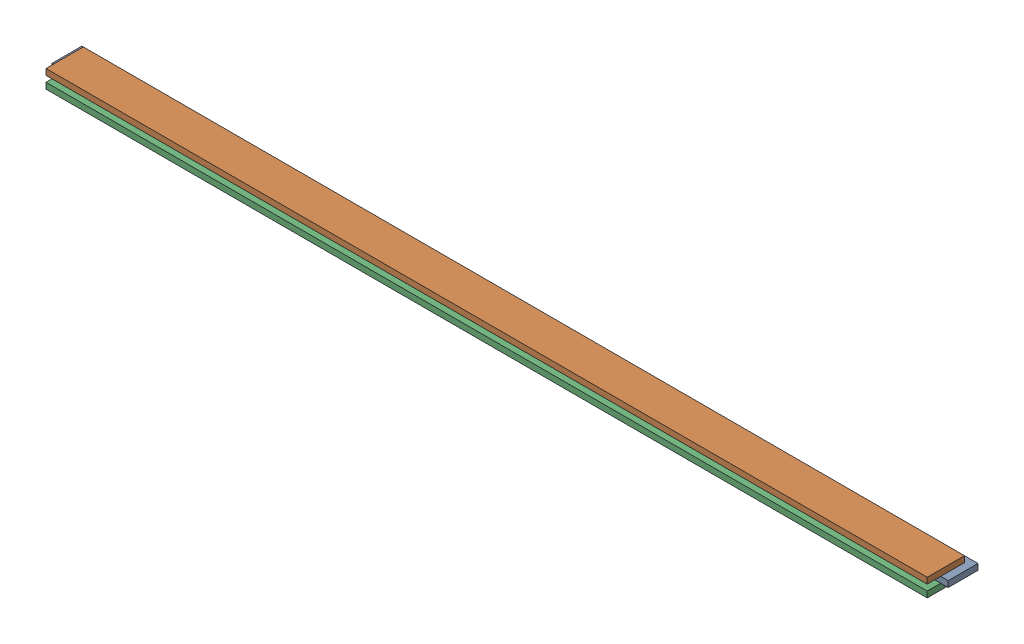
SolidWorks assembly БокП, configuration По умолчанию. Lengths in mm.
Overall size (1200 24 58).
3 component instances, 2 part files, 7 mates.
Components (placement in the parent):
- планкаСР_П-1: планкаСР_П [По умолчанию] at origin size (1200 8 40)
- планкаК_П-1: планкаК_П [По умолчанию] at (0 8 13) size (1180 8 50)
- планкаК_П-2: планкаК_П [По умолчанию] at (0 -8 13) size (1180 8 50)
Mates (geometry in assembly coordinates):
- Совпадение3: coordinate: point of планкаСР_П-1
- Совпадение4: coincident anti-aligned: plane of планкаСР_П-1 through (0 8 0) normal (0 1 0); plane of планкаК_П-1 through (-10 8 13) normal (0 -1 0)
- Расстояние2: distance = 10 mm aligned: plane of планкаСР_П-1 through (-600 8 -20) normal (-1 0 0); plane of планкаК_П-1 through (-590 16 -12) normal (-1 0 0)
- Расстояние1: distance = 8 mm aligned: plane of планкаК_П-1 through (-590 16 -12) normal (0 0 -1); plane of планкаСР_П-1 through (-600 8 -20) normal (0 0 -1)
- Совпадение7: coincident aligned: plane of планкаК_П-1 through (-600 16 38) normal (0 0 1); plane of планкаК_П-2 through (-600 0 38) normal (0 0 1)
- Совпадение8: coincident aligned: plane of планкаК_П-1 through (-600 16 -12) normal (-1 0 0); plane of планкаК_П-2 through (-600 0 -12) normal (-1 0 0)
- Совпадение9: coincident anti-aligned: plane of планкаСР_П-1 through (0 0 0) normal (0 -1 0); plane of планкаК_П-2 through (-10 0 13) normal (0 1 0)
